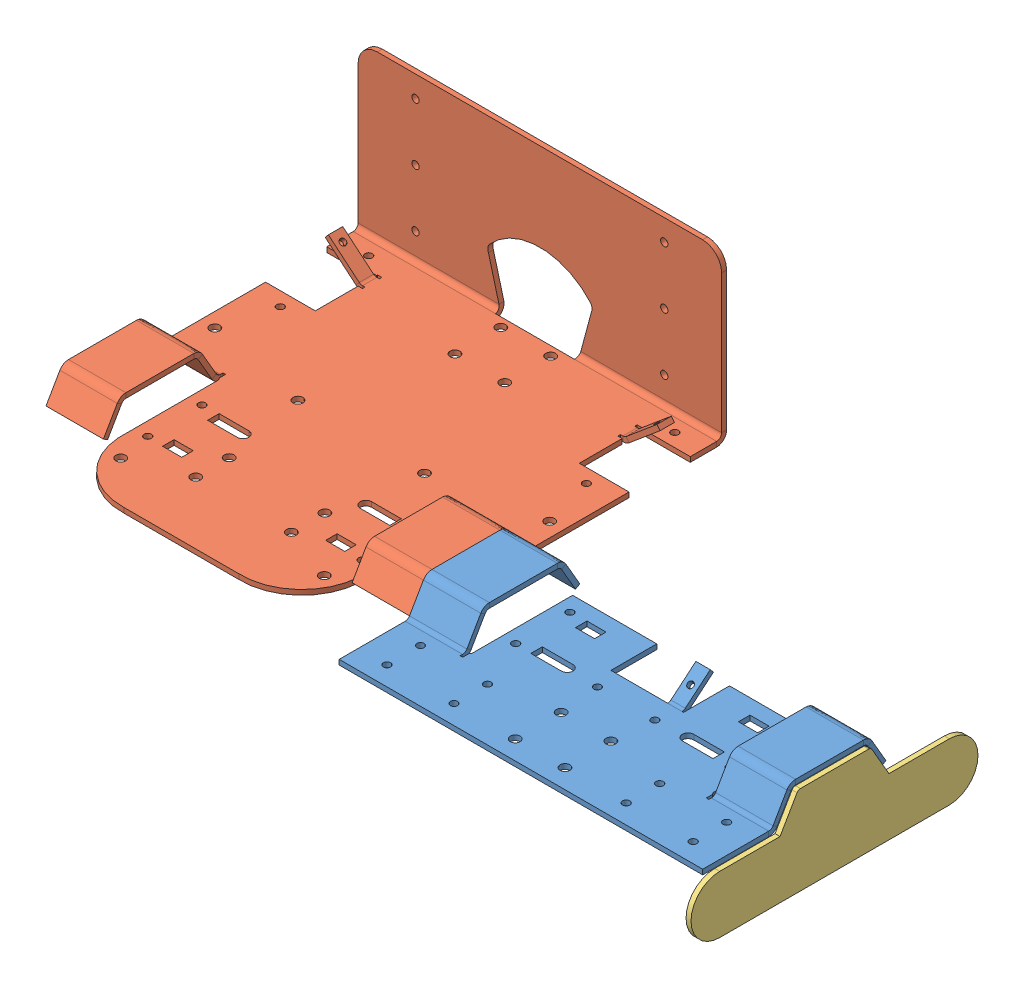
SolidWorks assembly TOOL TEST ASSM, configuration Default. Lengths in mm.
Overall size (242.95 74.81 134.12).
3 component instances, 3 part files, 4 mates.
Components (placement in the parent):
- PLATE, FRONT-1: PLATE, FRONT [Default] at (-33.6095 10.0133 10.9324) size (120.65 12.1 60.8)
- PLATE, REAR-1: PLATE, REAR [Default] at (-154.2595 10.0133 0.58) size (120.65 55.63 120.66)
- TOOL, WHEEL COVER CALIBRATION-1: TOOL, WHEEL COVER CALIBRATION [Default] at (28.3665 9.8788 25.9893) x (0 0 1) z (-1 0 0) size (95.25 29.46 1.65)
Mates (geometry in assembly coordinates):
- Coincident1: coincident: plane of PLATE, FRONT-1 through (-93.9345 22.1141 14.741) normal (0 1 0); plane of PLATE, REAR-1 through (-93.9345 22.1141 37.2828) normal (0 1 0)
- Coincident2: coincident: plane of PLATE, FRONT-1 through (-93.9345 11.6643 8.7078) normal (0 -0.5 0.866025); plane of PLATE, REAR-1 through (-93.9345 10.8388 8.2312) normal (0 -0.5 0.866025)
- Coincident3: coincident anti-aligned: plane of PLATE, FRONT-1 through (-93.9345 22.1141 38.236) normal (-1 0 0); plane of PLATE, REAR-1 through (-93.9345 22.1141 13.7878) normal (1 0 0)
- Coincident4: coincident anti-aligned: plane of PLATE, FRONT-1 through (26.7155 22.1141 14.741) normal (1 0 0); plane of TOOL, WHEEL COVER CALIBRATION-1 through (26.7155 0.3538 -12.1107) normal (-1 0 0)
